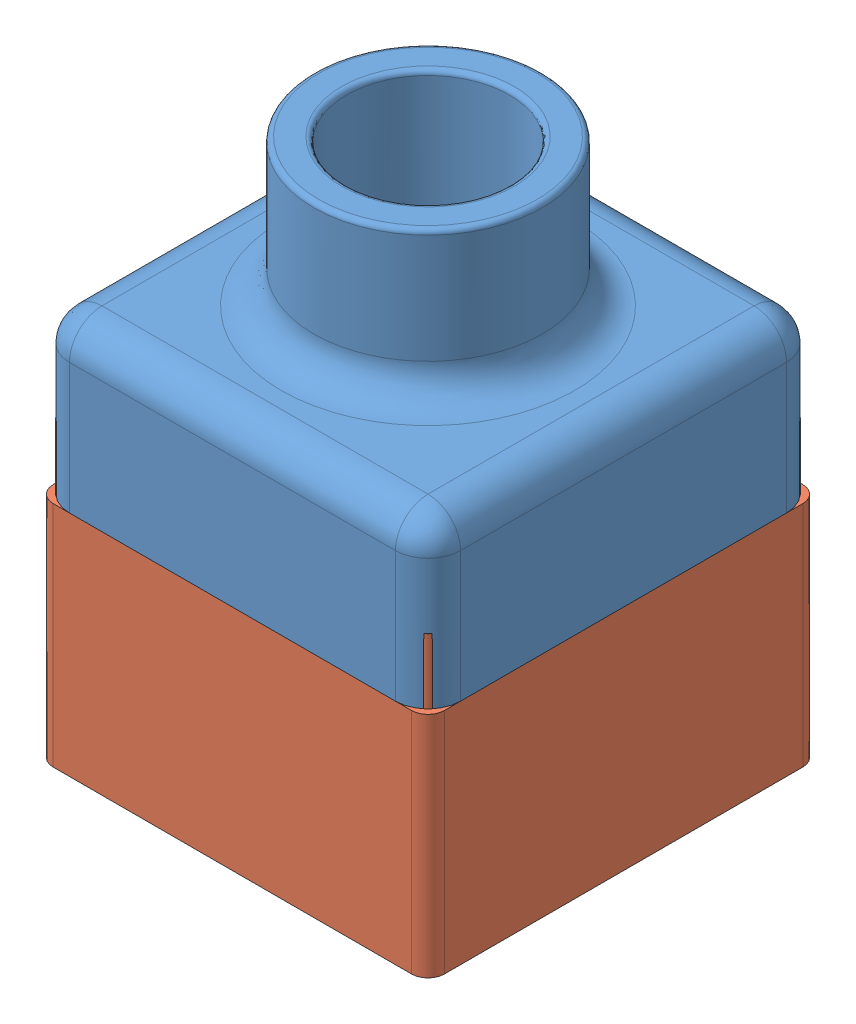
SolidWorks assembly leccion2ensamblaje, configuration Default. Lengths in mm.
Overall size (120 165 120).
2 component instances, 2 part files, 3 mates.
Components (placement in the parent):
- leccion1avilasanchez-3: leccion1avilasanchez [Default] at (-38.7287 37.2053 153.4515) size (120 95 120)
- leccion2avilasanchez-3: leccion2avilasanchez [Default] at (-38.7287 -32.7947 33.4515) x (1 0 0) z (0 1 0) size (120 120 90)
Mates (geometry in assembly coordinates):
- Coincident7: coincident anti-aligned: line of leccion1avilasanchez-3 through (-28.7287 37.2053 33.4515) axis (1 0 0); line of leccion2avilasanchez-3 through (76.2713 37.2053 33.4515) axis (-1 0 0)
- Coincident10: coincident aligned: line of leccion1avilasanchez-3 through (-28.7287 37.2053 153.4515) axis (1 0 0); line of leccion2avilasanchez-3 through (-33.7287 37.2053 153.4515) axis (1 0 0)
- Coincident11: coincident aligned: plane of leccion1avilasanchez-3 through (81.2713 87.2053 153.4515) normal (1 0 0); plane of leccion2avilasanchez-3 through (81.2713 57.2053 33.4515) normal (1 0 0)
